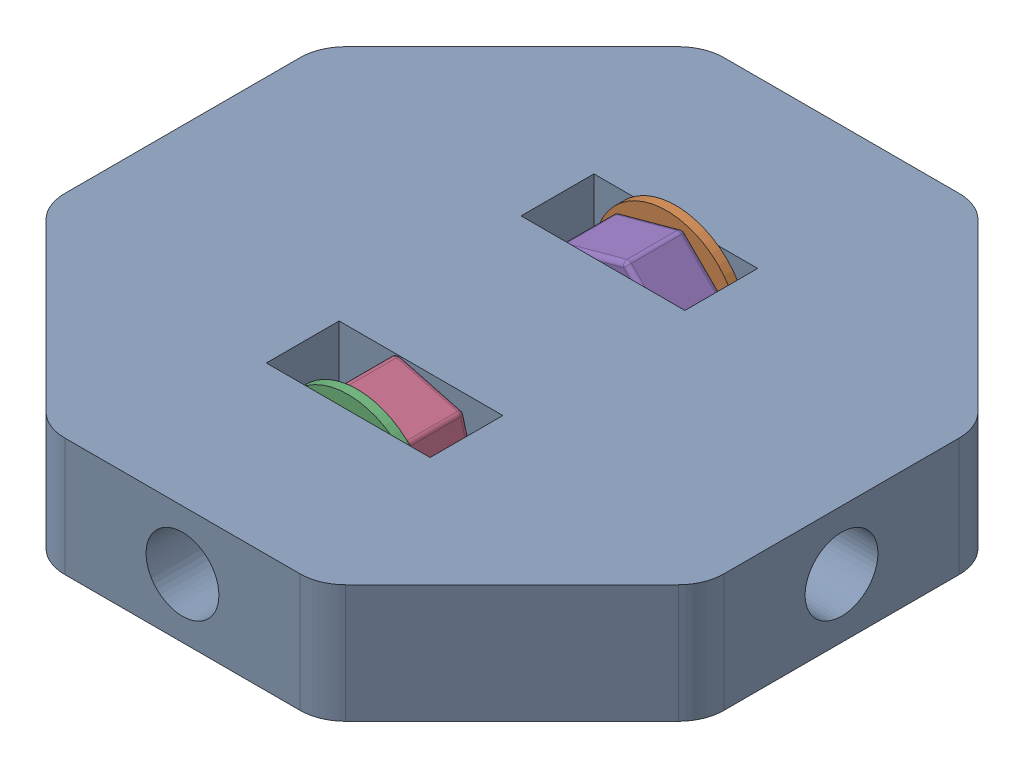
SolidWorks assembly Cross Brace, configuration Default. Lengths in mm.
Overall size (72.43 22.63 72.43).
5 component instances, 3 part files, 4 mates.
Components (placement in the parent):
- Cross Brace-1: Cross Brace [Default] at origin size (72.43 13 72.43)
- M8 Washer 16mm-1: M8 Washer 16mm [Default] at (0 6.5 -17) x (0.709711 -0.704493 0) z (0.704493 0.709711 0) size (16 1 16)
- M8 Washer 16mm-2: M8 Washer 16mm [Default] at (0 6.5 17) x (0.704493 0.709711 0) z (0.709711 -0.704493 0) size (16 1 16)
- M8 Nut-1: M8 Nut [Default] at (0 6.5 10.5) x (0.704493 0.709711 0) z (0.709711 -0.704493 0) size (14.85 6.5 12.99)
- M8 Nut-2: M8 Nut [Default] at (0 6.5 -10.5) x (0.709711 -0.704493 0) z (0.704493 0.709711 0) size (14.85 6.5 12.99)
Mates (geometry in assembly coordinates):
- Coincident8: coincident anti-aligned: circle of Cross Brace-1; circle of M8 Washer 16mm-1
- Coincident9: coincident anti-aligned: circle of Cross Brace-1; circle of M8 Washer 16mm-2
- Coincident11: coincident anti-aligned: circle of M8 Washer 16mm-1; circle of M8 Nut-2
- Coincident10: coincident anti-aligned: circle of M8 Washer 16mm-2; circle of M8 Nut-1
